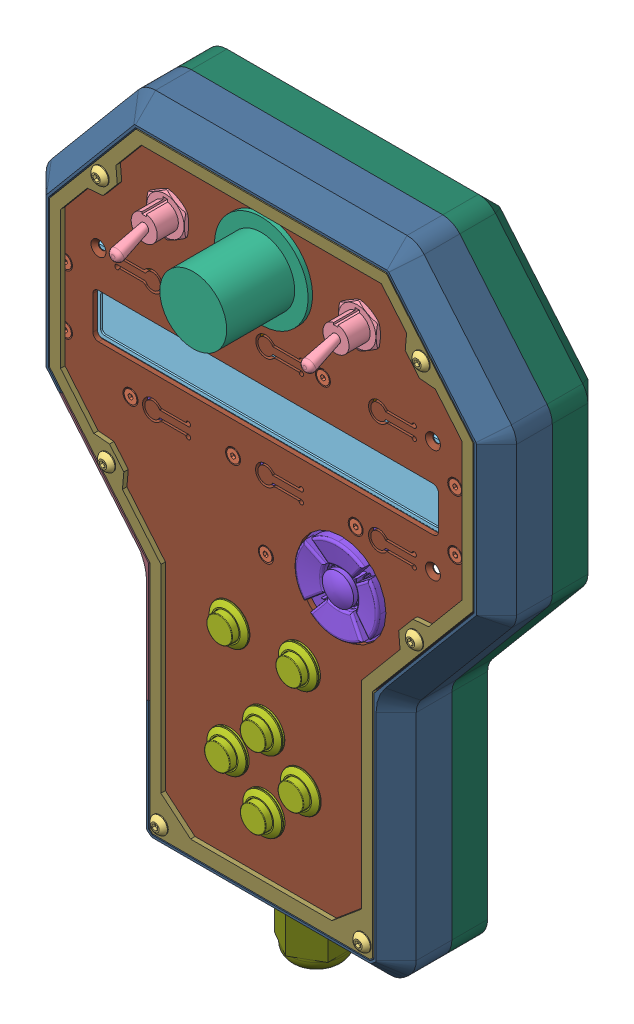
SolidWorks assembly Montagem, configuration Valor predeterminado. Lengths in mm.
Overall size (211 315 80.5).
60 component instances, 19 part files, 137 mates.
Components (placement in the parent):
- hex nut style 1 gradeab_din-3: hex nut style 1 gradeab_din [Hexagon Nut ISO 4032 - M4 - W - N] at (-95.2029 -0.5297 -15.05) x (-0.766044 -0.642788 0) z (0 0 1) size (7 8.08 3.2)
- hex nut style 1 gradeab_din-4: hex nut style 1 gradeab_din [Hexagon Nut ISO 4032 - M4 - W - N] at (42.9071 -0.5197 -15.05) x (0.766044 -0.642788 0) z (0 0 1) size (7 8.08 3.2)
- hex nut style 1 gradeab_din-5: hex nut style 1 gradeab_din [Hexagon Nut ISO 4032 - M4 - W - N] at (-69.6429 -49.9305 2.95) x (0.5 0.866025 0) z (0 0 1) size (7 8.08 3.2)
- hex nut style 1 gradeab_din-6: hex nut style 1 gradeab_din [Hexagon Nut ISO 4032 - M4 - W - N] at (33.6932 120.5695 2.95) x (0.766044 0.642788 0) z (0 0 1) size (7 8.08 3.2)
- hex nut style 1 gradeab_din-7: hex nut style 1 gradeab_din [Hexagon Nut ISO 4032 - M4 - W - N] at (17.3571 -99.7712 2.95) size (7 8.08 3.2)
- hex nut style 1 gradeab_din-8: hex nut style 1 gradeab_din [Hexagon Nut ISO 4032 - M4 - W - N] at (-85.979 120.5695 2.95) x (0.766044 -0.642788 0) z (0 0 1) size (7 8.08 3.2)
- hex nut style 1 gradeab_din-9: hex nut style 1 gradeab_din [Hexagon Nut ISO 4032 - M4 - W - N] at (-69.6429 -99.7712 2.95) size (7 8.08 3.2)
- hex nut style 1 gradeab_din-10: hex nut style 1 gradeab_din [Hexagon Nut ISO 4032 - M4 - W - N] at (45.8324 109.2141 -7.45) x (0.939693 -0.34202 0) z (0 0 -1) size (7 8.08 3.2)
- hex nut style 1 gradeab_din-11: hex nut style 1 gradeab_din [Hexagon Nut ISO 4032 - M4 - W - N] at (-71.6429 -129.7045 -7.45) x (0.5 0.866025 0) z (0 0 -1) size (7 8.08 3.2)
- hex nut style 1 gradeab_din-12: hex nut style 1 gradeab_din [Hexagon Nut ISO 4032 - M4 - W - N] at (19.3571 -129.7045 -7.45) x (1 0 0) z (0 0 -1) size (7 8.08 3.2)
- hex nut style 1 gradeab_din-13: hex nut style 1 gradeab_din [Hexagon Nut ISO 4032 - M4 - W - N] at (-98.1182 109.2141 -7.45) x (-0.939693 -0.34202 0) z (0 0 -1) size (7 8.08 3.2)
- socket countersunk head screw_din-8: socket countersunk head screw_din [DIN 7991 - M3 x 16 --- 12.8C] at (58.8311 39.2309 11.75) x (0 0 -1) z (1 0 0) size (16 5.7 5.7)
- socket countersunk head screw_din-9: socket countersunk head screw_din [DIN 7991 - M3 x 16 --- 12.8C] at (-86.7826 27.8805 11.75) x (0 0 -1) z (-0.923728 -0.383049 0) size (16 5.7 5.7)
- socket countersunk head screw_din-10: socket countersunk head screw_din [DIN 7991 - M3 x 16 --- 12.8C] at (-116.1689 65.7309 11.75) x (0 0 -1) z (-0.923728 -0.383049 0) size (16 5.7 5.7)
- socket countersunk head screw_din-11: socket countersunk head screw_din [DIN 7991 - M3 x 16 --- 12.8C] at (-0.483 78.4595 11.75) x (0 0 -1) z (0.923728 0.383049 0) size (16 5.7 5.7)
- socket countersunk head screw_din-12: socket countersunk head screw_din [DIN 7991 - M3 x 16 --- 12.8C] at (-116.1689 39.2309 11.75) x (0 0 -1) z (-0.923728 -0.383049 0) size (16 5.7 5.7)
- socket countersunk head screw_din-13: socket countersunk head screw_din [DIN 7991 - M3 x 16 --- 12.8C] at (-52.483 78.4595 11.75) x (0 0 -1) z (0.923728 0.383049 0) size (16 5.7 5.7)
- socket countersunk head screw_din-14: socket countersunk head screw_din [DIN 7991 - M3 x 16 --- 12.8C] at (58.8311 65.7309 11.75) x (0 0 -1) z (0.923728 0.383049 0) size (16 5.7 5.7)
- socket countersunk head screw_din-15: socket countersunk head screw_din [DIN 7991 - M3 x 16 --- 12.8C] at (14.2174 27.8805 11.75) x (0 0 -1) z (1 0 0) size (16 5.7 5.7)
- socket countersunk head screw_din-16: socket countersunk head screw_din [DIN 7991 - M3 x 16 --- 12.8C] at (-40.7826 27.8805 11.75) x (0 0 -1) z (0.277326 0.960776 0) size (16 5.7 5.7)
- socket countersunk head screw_din-17: socket countersunk head screw_din [DIN 7991 - M3 x 16 --- 12.8C] at (-26.2001 -3.0051 11.75) x (0 0 -1) z (-0.006263 -0.99998 0) size (16 5.7 5.7)
- hex nut style 1 gradeab_din-15: hex nut style 1 gradeab_din [Hexagon Nut ISO 4032 - M3 - W - N] at (-40.7826 27.8805 0.1586) x (0.012479 -0.999922 0) z (0 0 -1) size (5.5 6.35 2.4)
- hex nut style 1 gradeab_din-16: hex nut style 1 gradeab_din [Hexagon Nut ISO 4032 - M3 - W - N] at (-52.483 78.4595 0.1586) x (0.904381 -0.426726 0) z (0 0 -1) size (5.5 6.35 2.4)
- hex nut style 1 gradeab_din-17: hex nut style 1 gradeab_din [Hexagon Nut ISO 4032 - M3 - W - N] at (-0.483 78.4595 0.1586) x (-0.993944 0.109886 0) z (0 0 -1) size (5.5 6.35 2.4)
- hex nut style 1 gradeab_din-18: hex nut style 1 gradeab_din [Hexagon Nut ISO 4032 - M3 - W - N] at (14.2174 27.8805 0.1586) x (-0.816279 -0.577658 0) z (0 0 -1) size (5.5 6.35 2.4)
- hex nut style 1 gradeab_din-19: hex nut style 1 gradeab_din [Hexagon Nut ISO 4032 - M3 - W - N] at (-86.7826 27.8805 0.1586) x (-0.525463 -0.850817 0) z (0 0 -1) size (5.5 6.35 2.4)
- hex nut style 1 gradeab_din-20: hex nut style 1 gradeab_din [Hexagon Nut ISO 4032 - M3 - W - N] at (-116.1689 65.7309 -3.318) x (0.297598 -0.954691 0) z (0 0 -1) size (5.5 6.35 2.4)
- hex nut style 1 gradeab_din-21: hex nut style 1 gradeab_din [Hexagon Nut ISO 4032 - M3 - W - N] at (-116.1689 39.2309 -3.318) x (0.646896 0.762578 0) z (0 0 -1) size (5.5 6.35 2.4)
- hex nut style 1 gradeab_din-22: hex nut style 1 gradeab_din [Hexagon Nut ISO 4032 - M3 - W - N] at (58.8311 65.7309 -3.318) x (0.923728 0.383049 0) z (0 0 -1) size (5.5 6.35 2.4)
- hex nut style 1 gradeab_din-23: hex nut style 1 gradeab_din [Hexagon Nut ISO 4032 - M3 - W - N] at (58.8311 39.2309 -3.318) x (0.923728 0.383049 0) z (0 0 -1) size (5.5 6.35 2.4)
- hex nut style 1 gradeab_din-24: hex nut style 1 gradeab_din [Hexagon Nut ISO 4032 - M3 - W - N] at (-26.2001 -3.0051 0.1586) x (0.05846 -0.99829 0) z (0 0 -1) size (5.5 6.35 2.4)
- socket button head screw_iso-9: socket button head screw_iso [ISO 7380 - M4 x 16 --- 16N] at (45.8295 109.2085 15.95) x (0 0 -1) z (1 0 0) size (18.2 7.6 7.6)
- socket button head screw_iso-10: socket button head screw_iso [ISO 7380 - M4 x 16 --- 16N] at (-98.1153 109.2085 15.95) x (0 0 -1) z (0.767389 -0.641182 0) size (18.2 7.6 7.6)
- socket button head screw_iso-11: socket button head screw_iso [ISO 7380 - M4 x 16 --- 16N] at (-71.6429 -129.7005 15.95) x (0 0 -1) z (1 0 0) size (18.2 7.6 7.6)
- socket button head screw_iso-12: socket button head screw_iso [ISO 7380 - M4 x 16 --- 16N] at (19.3571 -129.7005 15.95) x (0 0 -1) z (1 0 0) size (18.2 7.6 7.6)
- socket button head screw_iso-14: socket button head screw_iso [ISO 7380 - M4 x 16 --- 16N] at (-95.1957 -0.5218 15.95) x (0 0 -1) z (1 0 0) size (18.2 7.6 7.6)
- socket button head screw_iso-13: socket button head screw_iso [ISO 7380 - M4 x 16 --- 16N] at (42.9099 -0.5218 15.95) x (0 0 -1) z (1 0 0) size (18.2 7.6 7.6)
- BCV3 112 103 - Controle chave geral-1: BCV3 112 103 - Controle chave geral [Default] at (-69.1429 108.0695 2.25) size (17 29 51.5)
- BCV3 112 103 - Controle chave geral-2: BCV3 112 103 - Controle chave geral [Default] at (16.8571 108.0695 2.25) size (17 29 51.5)
- LCD Display 4002-1: LCD Display 4002 [Valor predeterminado] at (-28.6689 52.4809 -3.8644) size (182 33.5 13.65)
- Botão emergencia-1: Botão emergencia [Valor predeterminado] at (-26.1429 108.0695 -28.25) x (0.351629 -0.93614 0) z (-0.93614 -0.351629 0) size (42 72.5 42)
- AV16HA-1: AV16HA [Valor predeterminado] at (-26.1429 -102.8813 -2.3) x (-0.899754 -0.436397 0) z (-0.436397 0.899754 0) size (21.5 29.33 19.15)
- AV16HA-2: AV16HA [Valor predeterminado] at (-42.1356 -37.8794 -3.25) x (0.225316 -0.974286 0) z (-0.974286 -0.225316 0) size (21.5 29.33 19.15)
- AV16HA-3: AV16HA [Valor predeterminado] at (-26.2096 -70.8635 -2.3) x (0.278036 0.960571 0) z (0.960571 -0.278036 0) size (21.5 29.33 19.15)
- AV16HA-4: AV16HA [Valor predeterminado] at (-10.177 -86.846 -3.25) x (0.980248 0.197772 0) z (0.197772 -0.980248 0) size (21.5 29.33 19.15)
- AV16HA-5: AV16HA [Valor predeterminado] at (-42.1948 -86.846 -2.3) x (0.999797 0.02015 0) z (0.02015 -0.999797 0) size (21.5 29.33 19.15)
- AV16HA-6: AV16HA [Valor predeterminado] at (-10.218 -37.8509 -2.3) x (-0.950101 -0.311942 0) z (-0.311942 0.950101 0) size (21.5 29.33 19.15)
- PCB-2: PCB [Valor predeterminado] at (-91.4326 8.3805 4.15) size (130.25 57.71 27.35)
- Teclas_Superiores-2: Teclas_Superiores [Valor predeterminado] at (-91.433 46.0455 4.15) size (130.25 12.75 19.2)
- TEC001 - Moldura -1: TEC001 - Moldura  [Valor predeterminado] at (-26.1429 -144.6278 -11.25) size (211 291 25)
- TEC002 - Placa Superior-1: TEC002 - Placa Superior [Valor predeterminado] at (-25.2999 1.2599 9.75) size (190 270 2)
- TEC003 - Moldura alumínio-1: TEC003 - Moldura alumínio [Valor predeterminado] at (-26.4426 -0.0902 11.75) size (190 270 2)
- TEC004 - Moldura Borracha-1: TEC004 - Moldura Borracha [Valor predeterminado] at (-26.6429 -144.6278 -11.25) size (64.1 110 25)
- TEC005 - Moldura Borracha Inferior-1: TEC005 - Moldura Borracha Inferior [Valor predeterminado] at (-26.6429 -144.6278 -11.25) size (64.1 110 25)
- TEC006 - Placa Inferior-1: TEC006 - Placa Inferior [Valor predeterminado] at (-25.2999 1.2599 -34.75) size (190 270 1.5) (hidden)
- TEC007 - Moldura  Inferior-1: TEC007 - Moldura  Inferior [Valor predeterminado] at (-26.1429 -144.6278 -11.25) size (211 291 25)
- Prensa cabo-1: Prensa cabo [Valor predeterminado] at (-26.1429 -154.9305 -11.0191) x (0.5 0 0.866025) z (0 -1 0) size (27.2 31.41 34)
- TEC008 - Pino-1: TEC008 - Pino [Valor predeterminado] at (-127.6429 32.3003 0.75) x (0.794362 -0.607445 0) z (0.607445 0.794362 0) size (4 25 4)
- TEC008 - Pino-2: TEC008 - Pino [Valor predeterminado] at (-80.1429 -114.1997 -24.25) x (0.610836 -0.791757 0) z (-0.791757 -0.610836 0) size (4 25 4)
- placa inferior-1: placa inferior [Valor predeterminado] at (-18.5596 4.7575 -324.8091) x (-1 0 0) z (0 0 -1) size (146 57.5 4) (hidden)
Mates (geometry in assembly coordinates):
- Coincidente2: coincident aligned: plane of TEC001 - Moldura -1 through (-26.1429 -144.6278 13.75) normal (0 0 1); plane of Botão emergencia-1 through (-33.5271 127.7285 13.75) normal (0 0 1)
- Distância7: distance = 1.5 mm aligned: plane of LCD Display 4002-1 through (-102.1429 60.5695 8.9626) normal (0 -1 0); plane of TEC002 - Placa Superior-1 through (-101.1429 62.0695 9.749) normal (0 -1 0)
- Coincidente22: coincident anti-aligned: plane of LCD Display 4002-1 through (-28.6689 52.4809 9.75) normal (0 0 1); plane of TEC002 - Placa Superior-1 through (-25.2999 1.2599 9.75) normal (0 0 -1)
- Distância8: distance = 1.5 mm aligned: plane of LCD Display 4002-1 through (-102.1429 43.8589 8.9626) normal (1 0 0); plane of TEC002 - Placa Superior-1 through (-103.6429 44.5695 9.749) normal (1 0 0)
- Coincidente24: coincident anti-aligned: plane of TEC001 - Moldura -1 through (-26.1429 -144.6278 9.75) normal (0 0 1); plane of TEC002 - Placa Superior-1 through (-25.2999 1.2599 9.75) normal (0 0 -1)
- Coincidente35: coincident anti-aligned: plane of TEC001 - Moldura -1 through (-49.8107 -84.1997 -11.25) normal (0 1 0); plane of TEC004 - Moldura Borracha-1 through (-50.3107 -84.1997 -11.25) normal (0 -1 0)
- Coincidente36: coincident anti-aligned: plane of TEC002 - Placa Superior-1 through (-25.2999 1.2599 9.75) normal (0 0 -1); plane of TEC004 - Moldura Borracha-1 through (-26.6429 -144.6278 9.75) normal (0 0 1)
- Concêntrico6: concentric aligned: cylinder of AV16HA-1 through (-26.1429 -102.8813 -2.3) axis (0 0 1) radius 7.95; cylinder of TEC002 - Placa Superior-1 through (-26.1429 -102.8813 9.749) axis (0 0 1) radius 8
- Tangente1: tangent: plane of TEC002 - Placa Superior-1 through (-25.2999 1.2599 11.75) normal (0 0 1); face of AV16HA-1
- Concêntrico9: concentric aligned: cylinder of AV16HA-4 through (-10.177 -86.846 -3.25) axis (0 0 1) radius 7.95; cylinder of TEC002 - Placa Superior-1 through (-10.177 -86.846 9.749) axis (0 0 1) radius 8
- Concêntrico10: concentric aligned: cylinder of AV16HA-3 through (-26.2096 -70.8635 -2.3) axis (0 0 1) radius 7.95; cylinder of TEC002 - Placa Superior-1 through (-26.2096 -70.8635 9.749) axis (0 0 1) radius 8
- Tangente2: tangent: plane of TEC002 - Placa Superior-1 through (-25.2999 1.2599 11.75) normal (0 0 1); face of AV16HA-5
- Tangente3: tangent: plane of TEC002 - Placa Superior-1 through (-25.2999 1.2599 11.75) normal (0 0 1); face of AV16HA-6
- Tangente4: tangent: plane of TEC002 - Placa Superior-1 through (-25.2999 1.2599 11.75) normal (0 0 1); face of AV16HA-4
- Tangente5: tangent: plane of TEC002 - Placa Superior-1 through (-25.2999 1.2599 11.75) normal (0 0 1); face of AV16HA-2
- Tangente6: tangent: plane of TEC002 - Placa Superior-1 through (-25.2999 1.2599 11.75) normal (0 0 1); face of AV16HA-3
- Concêntrico12: concentric anti-aligned: cylinder of Botão emergencia-1 through (-26.1429 108.0695 -50.7451) axis (0 0 -1) radius 15; cylinder of TEC002 - Placa Superior-1 through (-26.1429 108.0695 9.749) axis (0 0 1) radius 11.25
- Concêntrico13: concentric anti-aligned: cylinder of BCV3 112 103 - Controle chave geral-1 through (-69.1429 108.0695 23.25) axis (0 0 -1) radius 5.85; cylinder of TEC002 - Placa Superior-1 through (-69.1429 108.0695 9.749) axis (0 0 1) radius 6
- Concêntrico15: concentric anti-aligned: cylinder of BCV3 112 103 - Controle chave geral-2 through (16.8571 108.0695 23.25) axis (0 0 -1) radius 5.85; cylinder of TEC002 - Placa Superior-1 through (16.8571 108.0695 9.749) axis (0 0 1) radius 6
- Coincidente38: coincident anti-aligned: plane of BCV3 112 103 - Controle chave geral-1 through (-69.1429 117.8845 11.75) normal (0 0 -1); plane of TEC002 - Placa Superior-1 through (-25.2999 1.2599 11.75) normal (0 0 1)
- Coincidente39: coincident anti-aligned: plane of BCV3 112 103 - Controle chave geral-2 through (16.8571 117.8845 11.75) normal (0 0 -1); plane of TEC002 - Placa Superior-1 through (-25.2999 1.2599 11.75) normal (0 0 1)
- Coincidente40: coincident anti-aligned: plane of TEC001 - Moldura -1 through (-39.9429 -142.4305 -3.2826) normal (0.5 0 -0.866025); plane of Prensa cabo-1 through (-39.7429 -142.4305 -3.1671) normal (-0.5 0 0.866025)
- Coincidente41: coincident anti-aligned: plane of TEC001 - Moldura -1 through (-26.1429 -142.4305 4.6849) normal (-0.5 0 -0.866025); plane of Prensa cabo-1 through (-26.1429 -142.4305 4.6849) normal (0.5 0 0.866025)
- Coincidente42: coincident anti-aligned: plane of TEC001 - Moldura -1 through (-26.1429 -142.4305 -11.25) normal (0 1 0); plane of Prensa cabo-1 through (-26.1429 -142.4305 -11.0191) normal (0 -1 0)
- Distância9: distance = 0.5 mm anti-aligned: plane of TEC002 - Placa Superior-1 through (-121.1429 88.7866 11.75) normal (-1 0 0); plane of TEC001 - Moldura -1 through (-121.6429 88.9571 9.75) normal (1 0 0)
- Distância10: distance = 0.5 mm anti-aligned: plane of TEC002 - Placa Superior-1 through (30.0211 135.0695 11.75) normal (0 1 0); plane of TEC001 - Moldura -1 through (30.2446 135.5695 9.75) normal (0 -1 0)
- Coincidente49: coincident anti-aligned: plane of TEC002 - Placa Superior-1 through (-25.2999 1.2599 11.75) normal (0 0 1); plane of TEC003 - Moldura alumínio-1 through (-26.4426 -0.0902 11.75) normal (0 0 -1)
- Coincidente50: coincident aligned: plane of TEC002 - Placa Superior-1 through (-121.1429 88.7866 11.75) normal (-1 0 0); plane of TEC003 - Moldura alumínio-1 through (-121.1429 88.7866 13.75) normal (-1 0 0)
- Coincidente51: coincident aligned: plane of TEC002 - Placa Superior-1 through (-74.8228 -134.9305 11.75) normal (0 -1 0); plane of TEC003 - Moldura alumínio-1 through (-74.8228 -134.9305 13.75) normal (0 -1 0)
- Coincidente52: coincident aligned: plane of TEC001 - Moldura -1 through (-86.6429 -144.6278 13.75) normal (-1 0 0); plane of TEC004 - Moldura Borracha-1 through (-86.6429 -144.6278 13.75) normal (-1 0 0)
- Coincidente53: coincident aligned: plane of TEC001 - Moldura -1 through (-26.1429 145.5695 13.75) normal (0 1 0); plane of TEC007 - Moldura  Inferior-1 through (-26.1429 145.5695 13.75) normal (0 1 0)
- Coincidente54: coincident aligned: plane of TEC001 - Moldura -1 through (-204.8631 5.3363 13.75) normal (-0.766044 0.642788 0); plane of TEC007 - Moldura  Inferior-1 through (-204.8631 5.3363 13.75) normal (-0.766044 0.642788 0)
- Coincidente55: coincident aligned: plane of TEC001 - Moldura -1 through (152.5774 5.3363 13.75) normal (0.766044 0.642788 0); plane of TEC007 - Moldura  Inferior-1 through (152.5774 5.3363 13.75) normal (0.766044 0.642788 0)
- Coincidente56: coincident anti-aligned: plane of TEC006 - Placa Inferior-1 through (-25.2999 1.2599 -33.25) normal (0 0 1); plane of TEC007 - Moldura  Inferior-1 through (-26.1429 -144.6278 -33.25) normal (0 0 -1)
- Distância11: distance = 0.5 mm anti-aligned: plane of TEC006 - Placa Inferior-1 through (30.0211 135.0695 -33.25) normal (0 1 0); plane of TEC007 - Moldura  Inferior-1 through (30.2446 135.5695 -33.25) normal (0 -1 0)
- Distância12: distance = 0.5 mm anti-aligned: plane of TEC006 - Placa Inferior-1 through (-121.1429 88.7866 -33.25) normal (-1 0 0); plane of TEC007 - Moldura  Inferior-1 through (-121.6429 88.9571 -33.25) normal (1 0 0)
- Coincidente57: coincident aligned: plane of TEC007 - Moldura  Inferior-1 through (-26.1429 -144.6278 -11.25) normal (0 0 1); plane of TEC005 - Moldura Borracha Inferior-1 through (-26.6429 -144.6278 -11.25) normal (0 0 1)
- Coincidente58: coincident anti-aligned: plane of TEC007 - Moldura  Inferior-1 through (-49.8107 -84.1997 -11.25) normal (0 1 0); plane of TEC005 - Moldura Borracha Inferior-1 through (-50.3107 -84.1997 -11.25) normal (0 -1 0)
- Coincidente59: coincident aligned: plane of TEC007 - Moldura  Inferior-1 through (-7.3536 -128.8618 13.75) normal (-0.766044 -0.642788 0); plane of TEC005 - Moldura Borracha Inferior-1 through (-7.5602 -128.6156 13.75) normal (-0.766044 -0.642788 0)
- Paralelo2: parallel anti-aligned: plane of TEC001 - Moldura -1 through (30.2446 135.5695 9.75) normal (0 -1 0); plane of BCV3 112 103 - Controle chave geral-1 through (-77.1429 122.5695 10.25) normal (0 1 0)
- Paralelo3: parallel anti-aligned: plane of TEC001 - Moldura -1 through (30.2446 135.5695 9.75) normal (0 -1 0); plane of BCV3 112 103 - Controle chave geral-2 through (8.8571 122.5695 10.25) normal (0 1 0)
- Concêntrico17: concentric aligned: cylinder of TEC001 - Moldura -1 through (33.6932 120.5695 -11.25) axis (0 0 1) radius 2.2; cylinder of hex nut style 1 gradeab_din-6 through (33.6932 120.5695 -0.25) axis (0 0 1) radius 1.65
- Concêntrico18: concentric aligned: cylinder of TEC001 - Moldura -1 through (-85.979 120.5695 -11.25) axis (0 0 1) radius 2.2; cylinder of hex nut style 1 gradeab_din-8 through (-85.979 120.5695 -0.25) axis (0 0 1) radius 1.65
- Paralelo4: parallel anti-aligned: plane of TEC001 - Moldura -1 through (-90.1865 121.3114 -0.25) normal (0.939693 0.34202 0); plane of hex nut style 1 gradeab_din-8 through (-89.9591 121.2713 -0.25) normal (-0.939693 -0.34202 0)
- Paralelo5: parallel anti-aligned: plane of TEC001 - Moldura -1 through (-87.4403 124.5843 -0.25) normal (0.766044 -0.642788 0); plane of hex nut style 1 gradeab_din-8 through (-87.3613 124.3672 -0.25) normal (-0.766044 0.642788 0)
- Coincidente67: coincident anti-aligned: plane of TEC001 - Moldura -1 through (-26.1429 -144.6278 -0.25) normal (0 0 1); plane of hex nut style 1 gradeab_din-8 through (-91.3414 125.069 -0.25) normal (0 0 -1)
- Paralelo6: parallel anti-aligned: plane of TEC001 - Moldura -1 through (30.947 123.8424 -0.25) normal (0.939693 -0.34202 0); plane of hex nut style 1 gradeab_din-6 through (31.0955 123.6655 -0.25) normal (-0.939693 0.34202 0)
- Coincidente69: coincident anti-aligned: plane of TEC001 - Moldura -1 through (-26.1429 -144.6278 -0.25) normal (0 0 1); plane of hex nut style 1 gradeab_din-6 through (28.3309 116.07 -0.25) normal (0 0 -1)
- Concêntrico21: concentric aligned: cylinder of TEC004 - Moldura Borracha-1 through (-69.6429 -49.9305 -11.25) axis (0 0 1) radius 2.2; cylinder of hex nut style 1 gradeab_din-5 through (-69.6429 -49.9305 -0.25) axis (0 0 1) radius 1.65
- Paralelo9: parallel aligned: plane of TEC004 - Moldura Borracha-1 through (-65.9429 -52.0667 -0.25) normal (-1 0 0); plane of hex nut style 1 gradeab_din-5 through (-73.1429 -47.9097 -0.25) normal (-1 0 0)
- Coincidente76: coincident anti-aligned: plane of TEC004 - Moldura Borracha-1 through (-26.6429 -144.6278 -0.25) normal (0 0 1); plane of hex nut style 1 gradeab_din-5 through (-73.1429 -55.9927 -0.25) normal (0 0 -1)
- Concêntrico22: concentric aligned: cylinder of TEC001 - Moldura -1 through (17.3571 -99.7712 -11.25) axis (0 0 1) radius 2.2; cylinder of hex nut style 1 gradeab_din-7 through (17.3571 -99.7712 -0.25) axis (0 0 1) radius 1.65
- Paralelo10: parallel aligned: plane of TEC001 - Moldura -1 through (21.0571 -101.9074 -0.25) normal (-1 0 0); plane of hex nut style 1 gradeab_din-7 through (13.8571 -97.7505 -0.25) normal (-1 0 0)
- Coincidente78: coincident anti-aligned: plane of TEC001 - Moldura -1 through (-26.1429 -144.6278 -0.25) normal (0 0 1); plane of hex nut style 1 gradeab_din-7 through (10.3571 -99.7712 -0.25) normal (0 0 -1)
- Concêntrico23: concentric aligned: cylinder of TEC001 - Moldura -1 through (-69.6429 -99.7712 -11.25) axis (0 0 1) radius 2.2; cylinder of hex nut style 1 gradeab_din-9 through (-69.6429 -99.7712 -0.25) axis (0 0 1) radius 1.65
- Paralelo11: parallel aligned: plane of TEC001 - Moldura -1 through (-65.9429 -101.9074 -0.25) normal (-1 0 0); plane of hex nut style 1 gradeab_din-9 through (-73.1429 -97.7505 -0.25) normal (-1 0 0)
- Coincidente80: coincident anti-aligned: plane of TEC001 - Moldura -1 through (-26.1429 -144.6278 -0.25) normal (0 0 1); plane of hex nut style 1 gradeab_din-9 through (-76.6429 -99.7712 -0.25) normal (0 0 -1)
- Concêntrico24: concentric anti-aligned: cylinder of TEC001 - Moldura -1 through (-71.6429 -129.7045 -11.25) axis (0 0 1) radius 2.2; cylinder of hex nut style 1 gradeab_din-11 through (-71.6429 -129.7045 -4.25) axis (0 0 -1) radius 1.65
- Paralelo12: parallel anti-aligned: plane of TEC001 - Moldura -1 through (-67.9429 -127.5683 3.75) normal (-0.5 -0.866025 0); plane of hex nut style 1 gradeab_din-11 through (-68.1429 -127.6838 -4.25) normal (0.5 0.866025 0)
- Concêntrico25: concentric anti-aligned: cylinder of TEC001 - Moldura -1 through (19.3571 -129.7045 -11.25) axis (0 0 1) radius 2.2; cylinder of hex nut style 1 gradeab_din-12 through (19.3571 -129.7045 -4.25) axis (0 0 -1) radius 1.65
- Paralelo13: parallel aligned: plane of TEC001 - Moldura -1 through (15.6571 -131.8407 3.75) normal (1 0 0); plane of hex nut style 1 gradeab_din-12 through (22.8571 -131.7252 -4.25) normal (1 0 0)
- Concêntrico27: concentric anti-aligned: cylinder of TEC001 - Moldura -1 through (45.8324 109.2141 -11.25) axis (0 0 1) radius 2.2; cylinder of hex nut style 1 gradeab_din-10 through (45.8324 109.2141 -4.25) axis (0 0 -1) radius 1.65
- Paralelo14: parallel aligned: plane of TEC001 - Moldura -1 through (43.0861 112.487 3.75) normal (0.173648 -0.984808 0); plane of hex nut style 1 gradeab_din-10 through (48.4302 106.1182 -4.25) normal (0.173648 -0.984808 0)
- Concêntrico28: concentric anti-aligned: cylinder of TEC001 - Moldura -1 through (-98.1182 109.2141 -11.25) axis (0 0 1) radius 2.2; cylinder of hex nut style 1 gradeab_din-13 through (-98.1182 109.2141 -4.25) axis (0 0 -1) radius 1.65
- Paralelo15: parallel aligned: plane of TEC001 - Moldura -1 through (-99.5794 113.2289 3.75) normal (-0.173648 -0.984808 0); plane of hex nut style 1 gradeab_din-13 through (-96.7359 105.4164 -4.25) normal (-0.173648 -0.984808 0)
- Coincidente89: coincident anti-aligned: plane of TEC001 - Moldura -1 through (-26.1429 -144.6278 -11.25) normal (0 0 -1); plane of TEC007 - Moldura  Inferior-1 through (-26.1429 -144.6278 -11.25) normal (0 0 1)
- Concêntrico53: concentric anti-aligned: cone of TEC002 - Placa Superior-1 through (14.2174 27.8805 11.75) axis (0 0 -1); cylinder of socket countersunk head screw_din-15 through (14.2174 27.8805 11.75) axis (0 0 1) radius 1.5
- Concêntrico54: concentric anti-aligned: cone of TEC002 - Placa Superior-1 through (58.8311 39.2309 11.75) axis (0 0 -1); cylinder of socket countersunk head screw_din-8 through (58.8311 39.2309 11.75) axis (0 0 1) radius 1.5
- Concêntrico55: concentric anti-aligned: cone of TEC002 - Placa Superior-1 through (58.8311 65.7309 11.75) axis (0 0 -1); cylinder of socket countersunk head screw_din-14 through (58.8311 65.7309 11.75) axis (0 0 1) radius 1.5
- Concêntrico56: concentric anti-aligned: cone of TEC002 - Placa Superior-1 through (-0.483 78.4595 11.75) axis (0 0 -1); cylinder of socket countersunk head screw_din-11 through (-0.483 78.4595 11.75) axis (0 0 1) radius 1.5
- Concêntrico57: concentric anti-aligned: cone of TEC002 - Placa Superior-1 through (-52.483 78.4595 11.75) axis (0 0 -1); cylinder of socket countersunk head screw_din-13 through (-52.483 78.4595 11.75) axis (0 0 1) radius 1.5
- Concêntrico58: concentric aligned: circle of TEC002 - Placa Superior-1; cylinder of socket countersunk head screw_din-10 through (-116.1689 65.7309 11.75) axis (0 0 1) radius 1.5
- Concêntrico59: concentric aligned: cylinder of socket countersunk head screw_din-12 through (-116.1689 39.2309 11.75) axis (0 0 1) radius 1.5; circle of TEC002 - Placa Superior-1
- Concêntrico60: concentric anti-aligned: cone of TEC002 - Placa Superior-1 through (-86.7826 27.8805 11.75) axis (0 0 -1); cylinder of socket countersunk head screw_din-9 through (-86.7826 27.8805 11.75) axis (0 0 1) radius 1.5
- Coincidente105: coincident aligned: plane of TEC002 - Placa Superior-1 through (-25.2999 1.2599 11.75) normal (0 0 1); plane of socket countersunk head screw_din-15 through (14.2174 27.8805 11.75) normal (0 0 1)
- Coincidente106: coincident aligned: plane of TEC002 - Placa Superior-1 through (-25.2999 1.2599 11.75) normal (0 0 1); plane of socket countersunk head screw_din-8 through (58.8311 39.2309 11.75) normal (0 0 1)
- Coincidente107: coincident: plane of TEC002 - Placa Superior-1 through (-25.2999 1.2599 11.75) normal (0 0 1); line of socket countersunk head screw_din-14 through (58.1215 64.8054 11.75) axis (-0.383049 0.923728 0)
- Coincidente108: coincident aligned: plane of TEC002 - Placa Superior-1 through (-25.2999 1.2599 11.75) normal (0 0 1); plane of socket countersunk head screw_din-11 through (-0.483 78.4595 11.75) normal (0 0 1)
- Coincidente109: coincident aligned: plane of TEC002 - Placa Superior-1 through (-25.2999 1.2599 11.75) normal (0 0 1); plane of socket countersunk head screw_din-10 through (-116.1689 65.7309 11.75) normal (0 0 1)
- Coincidente110: coincident aligned: plane of TEC002 - Placa Superior-1 through (-25.2999 1.2599 11.75) normal (0 0 1); circle of socket countersunk head screw_din-13
- Coincidente111: coincident aligned: plane of TEC002 - Placa Superior-1 through (-25.2999 1.2599 11.75) normal (0 0 1); plane of socket countersunk head screw_din-9 through (-86.7826 27.8805 11.75) normal (0 0 1)
- Coincidente112: coincident aligned: plane of TEC002 - Placa Superior-1 through (-25.2999 1.2599 11.75) normal (0 0 1); plane of socket countersunk head screw_din-12 through (-116.1689 39.2309 11.75) normal (0 0 1)
- Concêntrico61: concentric anti-aligned: cone of TEC002 - Placa Superior-1 through (-40.7826 27.8805 11.75) axis (0 0 -1); cylinder of socket countersunk head screw_din-16 through (-40.7826 27.8805 11.75) axis (0 0 1) radius 1.5
- Coincidente113: coincident aligned: plane of TEC002 - Placa Superior-1 through (-25.2999 1.2599 11.75) normal (0 0 1); plane of socket countersunk head screw_din-16 through (-40.7826 27.8805 11.75) normal (0 0 1)
- Coincidente114: coincident aligned: plane of TEC002 - Placa Superior-1 through (-25.2999 1.2599 11.75) normal (0 0 1); plane of socket countersunk head screw_din-17 through (-26.2001 -3.0051 11.75) normal (0 0 1)
- Concêntrico63: concentric aligned: cone of socket countersunk head screw_din-13 through (-52.483 78.4595 -4.25) axis (0 0 -1); cylinder of hex nut style 1 gradeab_din-16 through (-52.483 78.4595 25.1961) axis (0 0 -1) radius 1.5
- Concêntrico64: concentric anti-aligned: cylinder of socket countersunk head screw_din-11 through (-0.483 78.4595 11.75) axis (0 0 1) radius 1.5; cylinder of hex nut style 1 gradeab_din-17 through (-0.483 78.4595 25.1961) axis (0 0 -1) radius 1.5
- Concêntrico65: concentric anti-aligned: cylinder of socket countersunk head screw_din-15 through (14.2174 27.8805 11.75) axis (0 0 1) radius 1.5; cylinder of hex nut style 1 gradeab_din-18 through (14.2174 27.8805 25.1961) axis (0 0 -1) radius 1.5
- Concêntrico66: concentric anti-aligned: cylinder of socket countersunk head screw_din-9 through (-86.7826 27.8805 11.75) axis (0 0 1) radius 1.5; cylinder of hex nut style 1 gradeab_din-19 through (-86.7826 27.8805 25.1961) axis (0 0 -1) radius 1.5
- Concêntrico67: concentric anti-aligned: cylinder of socket countersunk head screw_din-10 through (-116.1689 65.7309 11.75) axis (0 0 1) radius 1.5; cylinder of hex nut style 1 gradeab_din-20 through (-116.1689 65.7309 21.7195) axis (0 0 -1) radius 1.5
- Coincidente118: coincident anti-aligned: plane of LCD Display 4002-1 through (-28.6689 52.4809 -0.918) normal (0 0 -1); plane of hex nut style 1 gradeab_din-20 through (-119.2005 64.7859 -0.918) normal (0 0 1)
- Concêntrico68: concentric anti-aligned: cylinder of socket countersunk head screw_din-12 through (-116.1689 39.2309 11.75) axis (0 0 1) radius 1.5; cylinder of hex nut style 1 gradeab_din-21 through (-116.1689 39.2309 21.7195) axis (0 0 -1) radius 1.5
- Coincidente119: coincident anti-aligned: plane of LCD Display 4002-1 through (-28.6689 52.4809 -0.918) normal (0 0 -1); plane of hex nut style 1 gradeab_din-21 through (-113.7474 37.1768 -0.918) normal (0 0 1)
- Concêntrico69: concentric anti-aligned: cylinder of socket countersunk head screw_din-14 through (58.8311 65.7309 11.75) axis (0 0 1) radius 1.5; cylinder of hex nut style 1 gradeab_din-22 through (58.8311 65.7309 21.7195) axis (0 0 -1) radius 1.5
- Coincidente120: coincident anti-aligned: plane of LCD Display 4002-1 through (-28.6689 52.4809 -0.918) normal (0 0 -1); plane of hex nut style 1 gradeab_din-22 through (60.0474 62.7977 -0.918) normal (0 0 1)
- Concêntrico70: concentric anti-aligned: cylinder of socket countersunk head screw_din-8 through (58.8311 39.2309 11.75) axis (0 0 1) radius 1.5; cylinder of hex nut style 1 gradeab_din-23 through (58.8311 39.2309 21.7195) axis (0 0 -1) radius 1.5
- Coincidente121: coincident anti-aligned: plane of LCD Display 4002-1 through (-28.6689 52.4809 -0.918) normal (0 0 -1); plane of hex nut style 1 gradeab_din-23 through (60.0474 36.2977 -0.918) normal (0 0 1)
- Concêntrico71: concentric anti-aligned: cylinder of socket countersunk head screw_din-17 through (-26.2001 -3.0051 11.75) axis (0 0 1) radius 1.5; cylinder of hex nut style 1 gradeab_din-24 through (-26.2001 -3.0051 2.5586) axis (0 0 -1) radius 1.25
- Concêntrico72: concentric aligned: cylinder of TEC003 - Moldura alumínio-1 through (45.8295 109.2085 11.749) axis (0 0 1) radius 2.1; cylinder of socket button head screw_iso-9 through (45.8295 109.2085 15.95) axis (0 0 1) radius 3.8
- Coincidente124: coincident anti-aligned: plane of TEC003 - Moldura alumínio-1 through (-26.4426 -0.0902 13.75) normal (0 0 1); plane of socket button head screw_iso-9 through (45.8295 111.2085 13.75) normal (0 0 -1)
- Concêntrico73: concentric aligned: cylinder of TEC003 - Moldura alumínio-1 through (-98.1153 109.2085 11.749) axis (0 0 1) radius 2.1; cylinder of socket button head screw_iso-10 through (-98.1153 109.2085 15.95) axis (0 0 1) radius 3.8
- Coincidente125: coincident anti-aligned: plane of TEC003 - Moldura alumínio-1 through (-26.4426 -0.0902 13.75) normal (0 0 1); plane of socket button head screw_iso-10 through (-96.8329 110.7433 13.75) normal (0 0 -1)
- Concêntrico74: concentric aligned: cylinder of TEC003 - Moldura alumínio-1 through (-71.6429 -129.7005 11.749) axis (0 0 1) radius 2.1; cylinder of socket button head screw_iso-11 through (-71.6429 -129.7005 15.95) axis (0 0 1) radius 3.8
- Coincidente126: coincident anti-aligned: plane of TEC003 - Moldura alumínio-1 through (-26.4426 -0.0902 13.75) normal (0 0 1); plane of socket button head screw_iso-11 through (-71.6429 -127.7005 13.75) normal (0 0 -1)
- Concêntrico75: concentric aligned: cylinder of TEC003 - Moldura alumínio-1 through (19.3571 -129.7005 11.749) axis (0 0 1) radius 2.1; cylinder of socket button head screw_iso-12 through (19.3571 -129.7005 15.95) axis (0 0 1) radius 3.8
- Coincidente127: coincident anti-aligned: plane of TEC003 - Moldura alumínio-1 through (-26.4426 -0.0902 13.75) normal (0 0 1); plane of socket button head screw_iso-12 through (19.3571 -127.7005 13.75) normal (0 0 -1)
- Concêntrico76: concentric anti-aligned: cylinder of socket countersunk head screw_din-16 through (-40.7826 27.8805 11.75) axis (0 0 1) radius 1.5; cylinder of hex nut style 1 gradeab_din-15 through (-40.7826 27.8805 2.5586) axis (0 0 -1) radius 1.25
- Concêntrico77: concentric aligned: cylinder of TEC007 - Moldura  Inferior-1 through (-127.6429 32.3003 -24.25) axis (0 0 1) radius 2.2; cylinder of TEC008 - Pino-1 through (-127.6429 32.3003 -24.25) axis (0 0 1) radius 2
- Coincidente138: coincident anti-aligned: plane of TEC007 - Moldura  Inferior-1 through (-127.6429 32.3003 -24.25) normal (0 0 1); plane of TEC008 - Pino-1 through (-127.6429 32.3003 -24.25) normal (0 0 -1)
- Concêntrico78: concentric anti-aligned: cylinder of TEC007 - Moldura  Inferior-1 through (-80.1429 -114.1997 -24.25) axis (0 0 1) radius 2.2; cylinder of TEC008 - Pino-2 through (-80.1429 -114.1997 0.75) axis (0 0 -1) radius 2
- Coincidente139: coincident anti-aligned: plane of TEC007 - Moldura  Inferior-1 through (-80.1429 -114.1997 -24.25) normal (0 0 1); plane of TEC008 - Pino-2 through (-80.1429 -114.1997 -24.25) normal (0 0 -1)
- Coincidente140: coincident anti-aligned: plane of TEC003 - Moldura alumínio-1 through (-26.4426 -0.0902 13.75) normal (0 0 1); plane of socket button head screw_iso-14 through (-95.1957 1.4782 13.75) normal (0 0 -1)
- Concêntrico80: concentric aligned: cylinder of TEC003 - Moldura alumínio-1 through (-95.1957 -0.5218 11.749) axis (0 0 1) radius 2.1; cylinder of socket button head screw_iso-14 through (-95.1957 -0.5218 15.95) axis (0 0 1) radius 2
- Coincidente141: coincident anti-aligned: plane of TEC003 - Moldura alumínio-1 through (-26.4426 -0.0902 13.75) normal (0 0 1); plane of socket button head screw_iso-13 through (42.9099 1.4782 13.75) normal (0 0 -1)
- Concêntrico82: concentric aligned: cylinder of TEC003 - Moldura alumínio-1 through (42.9099 -0.5218 11.749) axis (0 0 1) radius 2.1; cylinder of socket button head screw_iso-13 through (42.9099 -0.5218 15.95) axis (0 0 1) radius 2
- Concêntrico83: concentric anti-aligned: cylinder of hex nut style 1 gradeab_din-3 through (-95.2029 -0.5297 -18.25) axis (0 0 1) radius 1.65; cylinder of TEC005 - Moldura Borracha Inferior-1 through (-95.2029 -0.5297 -11.249) axis (0 0 -1) radius 2.1
- Paralelo16: parallel aligned: plane of hex nut style 1 gradeab_din-3 through (-96.5852 -4.3274 -18.25) normal (-0.766044 -0.642788 0); plane of TEC005 - Moldura Borracha Inferior-1 through (-90.9954 0.2122 -26.25) normal (-0.766044 -0.642788 0)
- Coincidente143: coincident: plane of hex nut style 1 gradeab_din-3 through (-89.8406 3.9698 -18.25) normal (0 0 -1); line of TEC005 - Moldura Borracha Inferior-1 through (-93.7417 3.485 -18.25) axis (0.642788 -0.766044 0)
- Concêntrico84: concentric aligned: cylinder of hex nut style 1 gradeab_din-4 through (42.9071 -0.5197 -18.25) axis (0 0 1) radius 1.65; cylinder of TEC007 - Moldura  Inferior-1 through (42.9071 -0.5197 -36.251) axis (0 0 1) radius 2.2
- Paralelo17: parallel aligned: plane of hex nut style 1 gradeab_din-4 through (46.8872 -1.2215 -18.25) normal (0.766044 -0.642788 0); plane of TEC007 - Moldura  Inferior-1 through (41.4459 3.495 -26.25) normal (0.766044 -0.642788 0)
- Coincidente145: coincident: plane of hex nut style 1 gradeab_din-4 through (37.5448 3.9798 -18.25) normal (0 0 -1); line of TEC007 - Moldura  Inferior-1 through (38.6996 0.2222 -18.25) axis (0.642788 0.766044 0)
- Coincidente146: coincident: plane of hex nut style 1 gradeab_din-10 through (39.2545 111.6083 -4.25) normal (0 0 1); line of TEC001 - Moldura -1 through (43.0861 112.487 -4.25) axis (-0.34202 -0.939693 0)
- Coincidente147: coincident: plane of hex nut style 1 gradeab_din-13 through (-91.5403 111.6083 -4.25) normal (0 0 1); line of TEC001 - Moldura -1 through (-99.5794 113.2289 -4.25) axis (-0.642788 -0.766044 0)
- Coincidente148: coincident: plane of hex nut style 1 gradeab_din-12 through (12.3571 -129.7045 -4.25) normal (0 0 1); moEndPointRef_w of TEC001 - Moldura -1
- Coincidente149: coincident: plane of hex nut style 1 gradeab_din-11 through (-75.1429 -135.7667 -4.25) normal (0 0 1); line of TEC001 - Moldura -1 through (-71.6429 -125.4321 -4.25) axis (-0.866025 -0.5 0)
- Distância13: distance = 5.6 mm anti-aligned: plane of PCB-2 through (-64.1256 -24.1545 4.15) normal (0 0 1); plane of TEC002 - Placa Superior-1 through (-25.2999 1.2599 9.75) normal (0 0 -1)
- Concêntrico86: concentric anti-aligned: circle of PCB-2; cylinder of TEC002 - Placa Superior-1 through (7.7564 1.0695 9.749) axis (0 0 1) radius 20
- Paralelo18: parallel aligned: plane of PCB-2 through (38.6944 33.3805 2.5586) normal (1 0 0); plane of TEC002 - Placa Superior-1 through (68.8571 88.7866 11.75) normal (1 0 0)
- Coincidente153: coincident aligned: plane of PCB-2 through (-64.1256 -24.1545 4.15) normal (0 0 1); plane of Teclas_Superiores-2 through (-91.433 71.9185 4.15) normal (0 0 1)
- Coincidente154: coincident aligned: plane of PCB-2 through (-91.5596 8.3805 2.5586) normal (-1 0 0); plane of Teclas_Superiores-2 through (-91.56 72.0455 2.5586) normal (-1 0 0)
- Concêntrico87: concentric aligned: cylinder of AV16HA-5 through (-42.1948 -86.846 -2.3) axis (0 0 1) radius 7.95; cylinder of TEC002 - Placa Superior-1 through (-42.1948 -86.846 9.749) axis (0 0 1) radius 8
- Concêntrico88: concentric aligned: cylinder of AV16HA-6 through (-10.218 -37.8509 -2.3) axis (0 0 1) radius 7.95; cylinder of TEC002 - Placa Superior-1 through (-10.218 -37.8509 9.749) axis (0 0 1) radius 8
- Concêntrico89: concentric aligned: cylinder of AV16HA-2 through (-42.1356 -37.8794 -3.25) axis (0 0 1) radius 6.25; cylinder of TEC002 - Placa Superior-1 through (-42.1356 -37.8794 9.749) axis (0 0 1) radius 8
- Concêntrico90: concentric anti-aligned: cylinder of Teclas_Superiores-2 through (-26.1329 77.7395 7.958) axis (0 0 -1) radius 1.75; cylinder of TEC002 - Placa Superior-1 through (-26.1329 77.7395 1.75) axis (0 0 1) radius 3.5
- Coincidente156: coincident aligned: plane of PCB-2 through (-91.5596 8.3805 2.5586) normal (-1 0 0); plane of placa inferior-1 through (-91.5596 8.5075 -326.8091) normal (-1 0 0)
- Coincidente157: coincident aligned: plane of PCB-2 through (-91.4326 33.5075 2.5586) normal (0 1 0); plane of placa inferior-1 through (54.4404 33.5075 -326.8091) normal (0 1 0)
- Paralelo19: parallel aligned: plane of PCB-2 through (-64.1256 -24.1545 2.5586) normal (0 0 -1); plane of placa inferior-1 through (-18.5596 4.7575 -326.8091) normal (0 0 -1)
